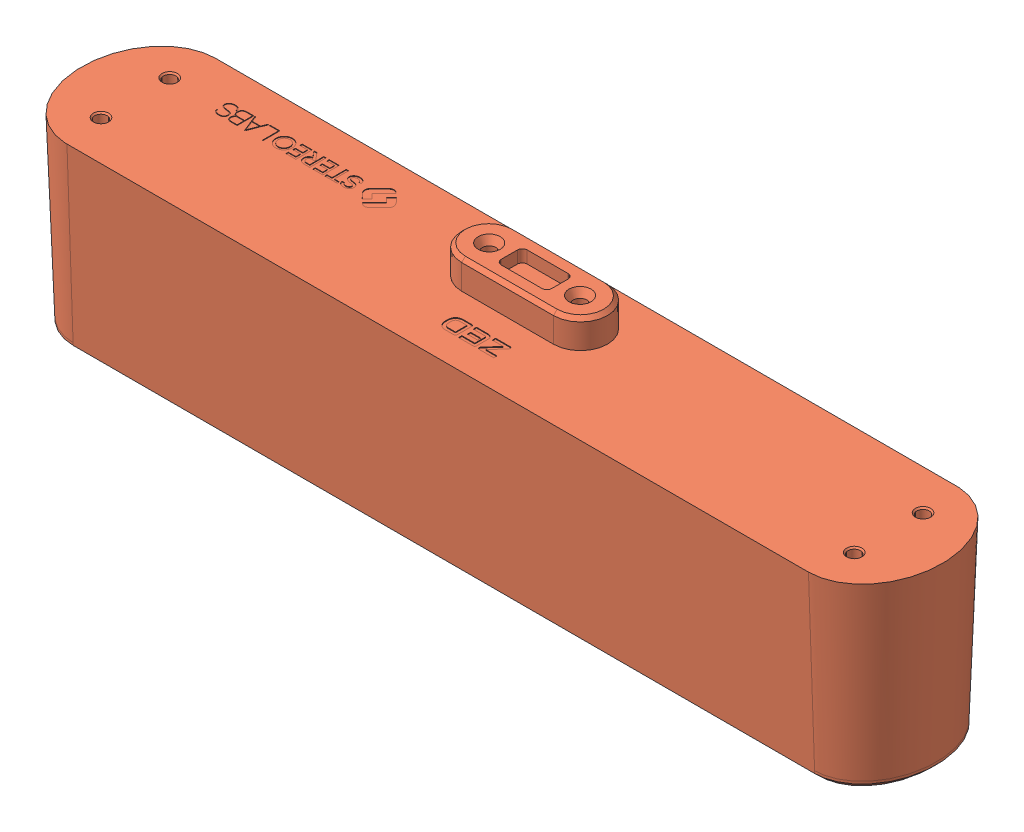
SolidWorks assembly ZED2i, configuration Default. Lengths in mm.
Overall size (175.3 43.1 32.76).
6 component instances, 4 part files, 0 mates.
Components (placement in the parent):
- ZED2i.step-1: ZED2i.step [Default] at origin size (175.3 43.1 32.76)
  - optic.step-1: optic.step [Default] at (-68.9685 6.689 8.643)
  - optic.step-2: optic.step [Default] at (51.0315 6.689 8.643)
  - ZED2_IP_Outer_with_lens.step-1: ZED2_IP_Outer_with_lens.step [Default] at origin
  - ZED2_IP_Outer_with_lens-0.step-1: ZED2_IP_Outer_with_lens-0.step [Default] at origin
  - ZED2_IP_Outer_with_lens-1.step-1: ZED2_IP_Outer_with_lens-1.step [Default] at origin
